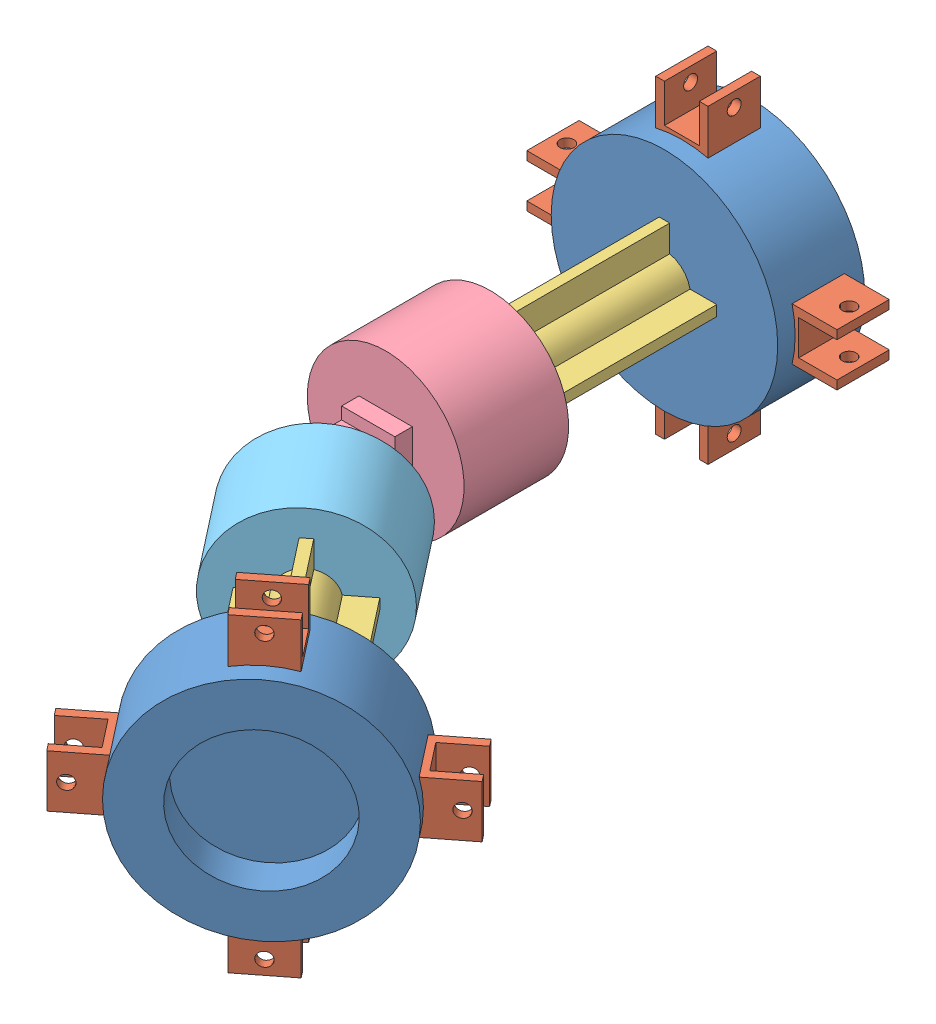
SolidWorks assembly Assem1, configuration Default. Lengths in mm.
Overall size (150.38 89 238.01).
14 component instances, 5 part files, 18 mates.
Components (placement in the parent):
- Face_PIG-1: Face_PIG [Default] at (30.0964 31.904 35.6847) size (65 65 25)
- Wheel_socket-1: Wheel_socket [Default] at (30.0964 54.404 48.1847) x (1 0 0) z (0 1 0) size (15 15 22)
- Wheel_socket-2: Wheel_socket [Default] at (52.5964 31.904 48.1847) x (0 -1 0) z (1 0 0) size (15 15 22)
- Wheel_socket-3: Wheel_socket [Default] at (30.0964 9.404 48.1847) x (-1 0 0) z (0 -1 0) size (15 15 22)
- Wheel_socket-4: Wheel_socket [Default] at (7.5964 31.904 48.1847) x (0 1 0) z (-1 0 0) size (15 15 22)
- Connector-1: Connector [Default] at (30.0964 31.904 50.6847) size (30 30 70)
- Flex_1-1: Flex_1 [Default] at (30.0964 31.904 110.6847) size (45 45 50)
- Flex_2-1: Flex_2 [Default] at (57.8093 31.905 191.1388) x (-0.787869 0 0.615843) z (-0.615843 0 -0.787869) size (45 45 50)
- Connector-2: Connector [Default] at (51.6509 31.905 183.2601) x (0.787869 0 -0.615843) z (0.615843 0 0.787869) size (30 30 70)
- Face_PIG-2: Face_PIG [Default] at (103.9976 31.905 250.229) x (0 1 0) z (-0.615843 0 -0.787869) size (65 65 25)
- Wheel_socket-5: Wheel_socket [Default] at (114.0266 31.905 226.5241) x (-0.615843 0 -0.787869) z (0.787869 0 -0.615843) size (15 15 22)
- Wheel_socket-6: Wheel_socket [Default] at (96.2995 9.405 240.3806) x (-0.615843 0 -0.787869) z (0 -1 0) size (15 15 22)
- Wheel_socket-7: Wheel_socket [Default] at (78.5725 31.905 254.2371) x (-0.615843 0 -0.787869) z (-0.787869 0 0.615843) size (15 15 22)
- Wheel_socket-8: Wheel_socket [Default] at (96.2995 54.405 240.3806) x (-0.615843 0 -0.787869) z (0 1 0) size (15 15 22)
Mates (geometry in assembly coordinates):
- Coincident1: coincident anti-aligned: plane of Face_PIG-1 through (30.0964 54.404 35.6847) normal (0 1 0); plane of Wheel_socket-1 through (30.0964 54.404 48.1847) normal (0 -1 0)
- Coincident2: coincident: point of Face_PIG-1; point of Wheel_socket-1
- Coincident3: coincident anti-aligned: plane of Face_PIG-1 through (30.0964 31.904 50.6847) normal (0 0 1); plane of Connector-1 through (30.0964 31.904 50.6847) normal (0 0 -1)
- Coincident4: coincident anti-aligned: plane of Face_PIG-1 through (30.0964 46.904 50.6847) normal (0 -1 0); plane of Connector-1 through (31.5964 46.904 120.6847) normal (0 1 0)
- Coincident5: coincident anti-aligned: plane of Face_PIG-1 through (15.0964 31.904 50.6847) normal (1 0 0); plane of Connector-1 through (15.0964 30.404 120.6847) normal (-1 0 0)
- Coincident6: coincident anti-aligned: plane of Connector-1 through (30.0964 31.904 120.6847) normal (0 0 1); plane of Flex_1-1 through (30.0964 31.904 120.6847) normal (0 0 -1)
- Coincident7: coincident anti-aligned: plane of Connector-1 through (31.5964 46.904 120.6847) normal (1 0 0); plane of Flex_1-1 through (31.5964 16.904 120.6847) normal (-1 0 0)
- Coincident8: coincident anti-aligned: plane of Connector-1 through (31.5964 46.904 120.6847) normal (0 1 0); plane of Flex_1-1 through (30.0964 46.904 120.6847) normal (0 -1 0)
- Coincident9: coincident anti-aligned: circle of Flex_1-1; circle of Flex_2-1
- Coincident10: coincident anti-aligned: plane of Flex_2-1 through (51.6509 31.905 183.2601) normal (0.615843 0 0.787869); plane of Connector-2 through (51.6509 31.905 183.2601) normal (-0.615843 0 -0.787869)
- Coincident11: coincident anti-aligned: plane of Flex_2-1 through (50.4691 16.905 184.1839) normal (0 1 0); plane of Connector-2 through (95.9417 16.905 237.4872) normal (0 -1 0)
- Coincident12: coincident anti-aligned: plane of Flex_2-1 through (39.8329 30.405 192.4978) normal (0.787869 0 -0.615843); plane of Connector-2 through (82.9419 30.405 247.6486) normal (-0.787869 0 0.615843)
- Coincident13: coincident anti-aligned: plane of Connector-2 through (94.7599 31.905 238.4109) normal (0.615843 0 0.787869); plane of Face_PIG-2 through (94.7599 31.905 238.4109) normal (-0.615843 0 -0.787869)
- Coincident14: coincident anti-aligned: plane of Connector-2 through (95.9417 46.905 237.4872) normal (0 1 0); plane of Face_PIG-2 through (94.7599 46.905 238.4109) normal (0 -1 0)
- Coincident15: coincident anti-aligned: plane of Connector-2 through (82.9419 30.405 247.6486) normal (-0.787869 0 0.615843); plane of Face_PIG-2 through (82.9419 30.405 247.6486) normal (0.787869 0 -0.615843)
- Coincident16: coincident anti-aligned: plane of Face_PIG-2 through (109.4078 39.405 220.6151) normal (0.615843 0 0.787869); plane of Wheel_socket-5 through (126.7409 24.405 207.0666) normal (-0.615843 0 -0.787869)
- Coincident17: coincident anti-aligned: plane of Face_PIG-2 through (121.7246 31.905 236.3725) normal (0.787869 0 -0.615843); plane of Wheel_socket-5 through (114.0266 31.905 226.5241) normal (-0.787869 0 0.615843)
- Coincident19: coincident anti-aligned: plane of Face_PIG-2 through (109.4078 39.405 220.6151) normal (0 -1 0); plane of Wheel_socket-5 through (135.9785 39.405 218.8846) normal (0 1 0)
